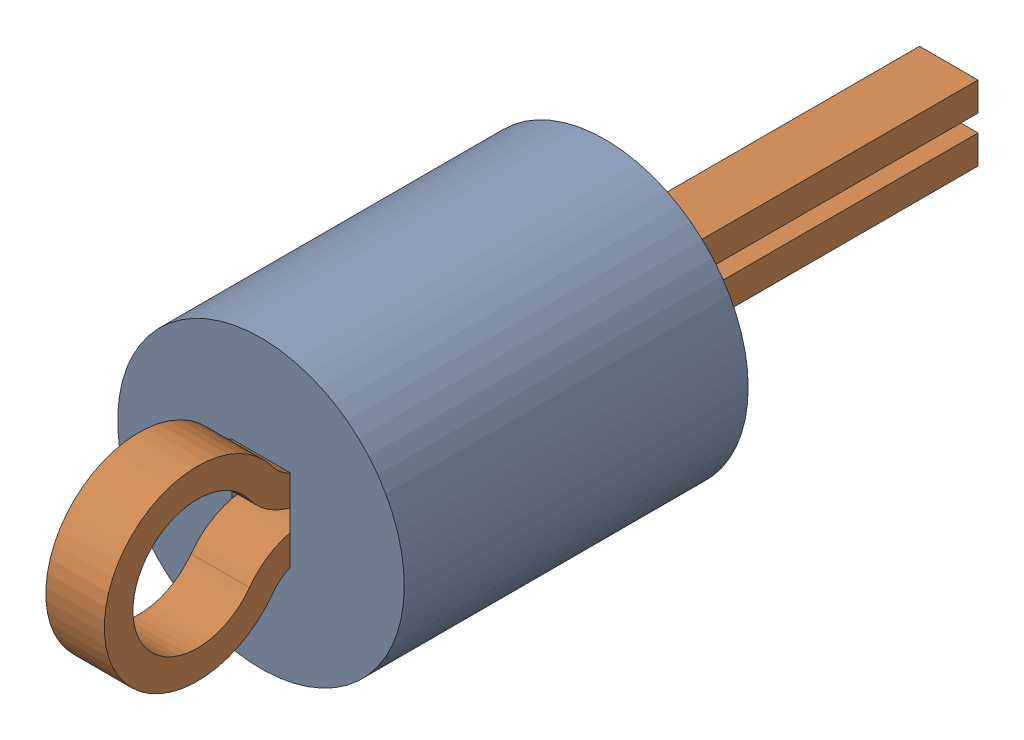
SolidWorks assembly TP1, configuration Default. Lengths in mm.
Overall size (2.5 2.5 7.62).
3 component instances, 2 part files, 0 mates.
Components (placement in the parent):
- Keystone_5002-1: Keystone_5002 [Default] at (37.0795 31.7529 0) size (2.5 2.5 7.62)
  - Keystone5002_white-1: Keystone5002_white [Default] at origin size (2.5 2.5 3)
  - Keystone500x_wire-1: Keystone500x_wire [Default] at origin size (0.51 1.62 7.62)
